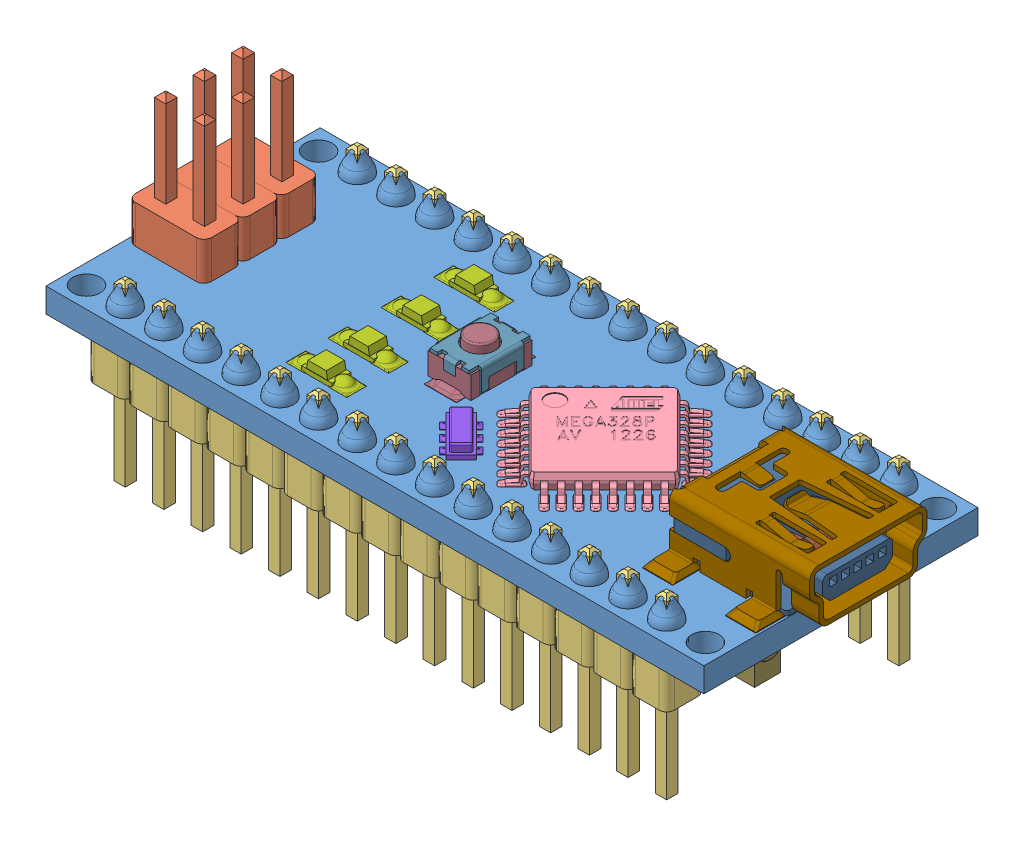
SolidWorks assembly arduino nano, configuration Predeterminado. Lengths in mm.
Overall size (45 18.6 18).
35 component instances, 18 part files, 0 mates.
Components (placement in the parent):
- nano-board-1: nano-board [Predeterminado] at origin size (43.2 4.61 18)
- 2pin_header__02-1: 2pin_header__02 [Predeterminado] at (-1.143 1.6 -7.62) size (5 11.75 2.54)
- 2pin_header__02-2: 2pin_header__02 [Predeterminado] at (-1.143 1.6 -5.08) size (5 11.75 2.54)
- 2pin_header__02-3: 2pin_header__02 [Predeterminado] at (-1.143 1.6 -10.16) size (5 11.75 2.54)
- 15pin_header__-1: 15pin_header__ [Predeterminado] x (0 0 1) z (1 0 0) size (2.54 11.75 38.1)
- 15pin_header__-2: 15pin_header__ [Predeterminado] at (0 0 -15.24) x (0 0 1) z (1 0 0) size (2.54 11.75 38.1)
- atmega328-1: atmega328 [Predeterminado] at (23.85 1.75 -7.62) x (-0.707107 0 0.707107) z (-0.707107 0 -0.707107) size (10 1.1 10)
- ftdi FT232rl-1: ftdi FT232rl [Predeterminado] at (29.05 0 -7.67) x (0 0 -1) z (-1 0 0) size (9.25 1.9 10.2)
- smt_resistor222-1: smt_resistor222 [Predeterminado] at (21.86 0 -5.8) x (0 0 -1) z (-1 0 0) size (1.7 0.6 3.8)
- smt_resistor222-2: smt_resistor222 [Predeterminado] at (21.86 0 -9) x (0 0 -1) z (-1 0 0) size (1.7 0.6 3.8)
- smt_resistor222-3: smt_resistor222 [Predeterminado] at (36.75 0 -7.6) x (0 0 -1) z (-1 0 0) size (1.7 0.6 3.8)
- smt_resistor222-4: smt_resistor222 [Predeterminado] at (36.75 0 -12) x (0 0 -1) z (-1 0 0) size (1.7 0.6 3.8)
- smt_resistor222-5: smt_resistor222 [Predeterminado] at (8.2 0 -2.6) x (0 0 -1) z (-1 0 0) size (1.7 0.6 3.8)
- led-1: led [Predeterminado] at (10.4 1.6 -2.8) size (4 0.9 1.55)
- led-2: led [Predeterminado] at (10.4 1.6 -5.55) size (4 0.9 1.55)
- led-3: led [Predeterminado] at (10.4 1.6 -12.5) size (4 0.9 1.55)
- led-4: led [Predeterminado] at (10.4 1.6 -9.05) size (4 0.9 1.55)
- 16mhz crystal - measured-1: 16mhz crystal - measured [Predeterminado] at (18.5113 1.6 -3.5541) x (0.707107 0 0.707107) z (-0.707107 0 0.707107) size (3.4 0.8 2.01)
- MINIUSB - MEASURED-1: MINIUSB - MEASURED [Predeterminado] at (38.98 1.65 -7.62) x (0 0 1) z (-1 0 0) size (11.03 4.95 10.42)
  - MINIUSBSHELL-1: MINIUSBSHELL [Predeterminado] at origin size (11.03 3.97 9.48)
  - MINIUSBCORE-1: MINIUSBCORE [Predeterminado] at (0 0 6.7) x (-1 0 0) z (0 0 -1) size (7.7 4.5 8.2)
  - MINI USB CONTACT-1: MINI USB CONTACT [Predeterminado] at (-1.6 0 5.7) x (-1 0 0) z (0 0 -1) size (0.53 2.55 9.41)
  - MINI USB CONTACT-2: MINI USB CONTACT [Predeterminado] at (-0.8 0 5.7) x (-1 0 0) z (0 0 -1) size (0.53 2.55 9.41)
  - MINI USB CONTACT-3: MINI USB CONTACT [Predeterminado] at (0 0 5.7) x (-1 0 0) z (0 0 -1) size (0.53 2.55 9.41)
  - MINI USB CONTACT-4: MINI USB CONTACT [Predeterminado] at (0.8 0 5.7) x (-1 0 0) z (0 0 -1) size (0.53 2.55 9.41)
  - MINI USB CONTACT-5: MINI USB CONTACT [Predeterminado] at (1.6 0 5.7) x (-1 0 0) z (0 0 -1) size (0.53 2.55 9.41)
- cap106C-1: cap106C [Predeterminado] at (37.2 0 -3.3) x (0 0 1) z (1 0 0) size (1.7 1.81 4)
- cap106C-2: cap106C [Predeterminado] at (7.9 0 -5.6) x (0 0 -1) z (-1 0 0) size (1.7 1.81 4)
- reset button-1: reset button [Predeterminado] at (15.25 1.6 -8.05) x (0 0 -1) z (1 0 0) size (5.21 2.15 3)
  - reset core-1: reset core [Predeterminado] at origin size (5.21 2.15 2.8)
  - reset shell-1: reset shell [Predeterminado] at (0 1.65 0) x (0 0 1) z (-1 0 0) size (3 1.65 4)
- nano - reg-1: nano - reg [Predeterminado] at (6.1 0 -10.16) x (0 0 -1) z (-1 0 0) size (6.5 1.69 8.3)
- NANO DIODE-1: NANO DIODE [Predeterminado] at (11.43 0 -4.2) x (0 0 1) z (1 0 0) size (4.92 1.38 1.7)
- 189 RESISTOR PACK-1: 189 RESISTOR PACK [Predeterminado] at (15.75 0 -10.85) x (0 0 1) z (1 0 0) size (3.2 0.51 3)
- 102 RESISTOR PACK-1: 102 RESISTOR PACK [Predeterminado] at (15.75 0 -5.2) x (0 0 1) z (1 0 0) size (3.2 0.51 3)
